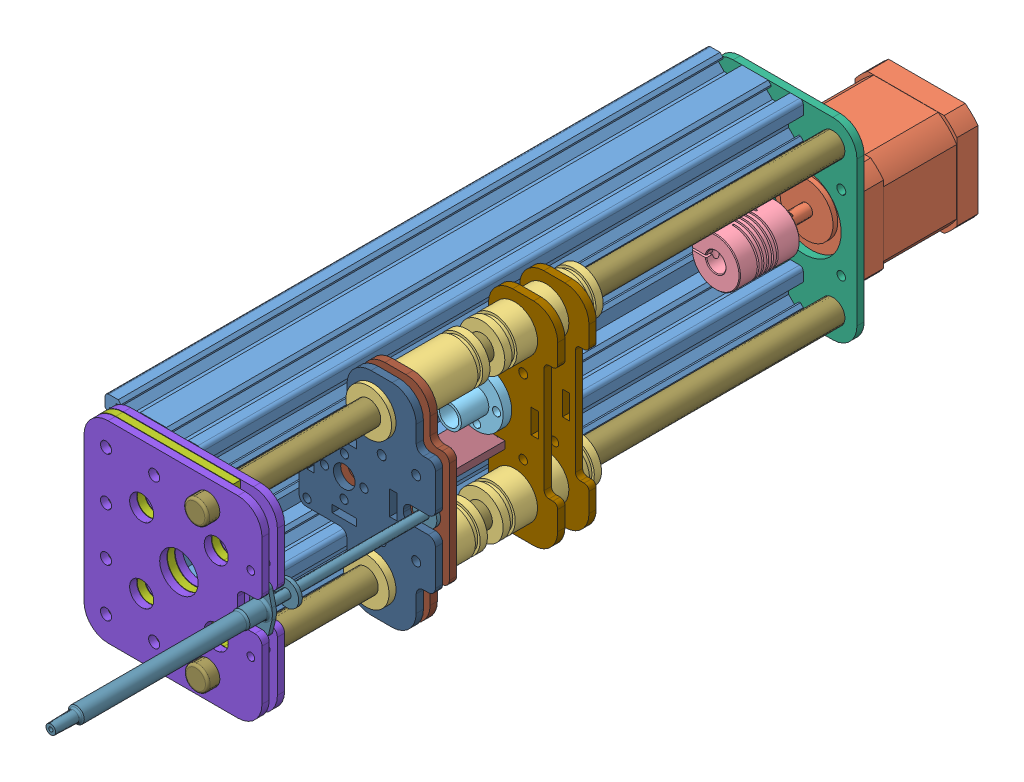
SolidWorks assembly pump_asembly02, configuration Default. Lengths in mm.
Overall size (78.17 88.03 393.93).
21 component instances, 15 part files, 31 mates.
Components (placement in the parent):
- C-Beam 40x80x250 Linear Rail-2: C-Beam 40x80x250 Linear Rail [Default] at (125.6746 -111.8662 -206.616) size (40 80 250)
- Nema 17 Stepper Motor-2: Nema 17 Stepper Motor [Default] at (145.9607 -111.6142 -209.692) size (42.42 42.42 72)
- bushing_10mm_id-1: bushing_10mm_id [Default] at (157.9607 -141.5917 -78.1172) x (0 0 -1) z (0.995692 -0.092726 0) size (40.86 19 19)
- bushing_10mm_id-2: bushing_10mm_id [Default] at (157.9607 -81.5917 -78.7968) x (0 0 -1) z (0.890907 0.454185 0) size (40.86 19 19)
- bushing_10mm_id-3: bushing_10mm_id [Default] at (157.9607 -141.5917 -30.7122) x (0 0 -1) z (0.92037 0.391048 0) size (40.86 19 19)
- bushing_10mm_id-4: bushing_10mm_id [Default] at (157.9607 -81.5917 -31.7606) x (0 0 -1) z (0.909573 -0.415544 0) size (40.86 19 19)
- Flexible Coupling 5mm x 8mm-1: Flexible Coupling 5mm x 8mm [Default] at (145.9021 -111.68 -194.9764) x (-1 0 0) z (0 0 -1) size (21.03 20 25)
- acme_nut_8mm-2: acme_nut_8mm [Default] at (145.9711 -111.5837 -74.1996) x (-1 0 0) z (0 1 0) size (22 15 22)
- laser_cut_end_plates_3mm-1: laser_cut_end_plates_3mm [Default] at (0 0 -209.616) size (61.43 80.03 3)
- laser_cut_front_plate_flat_3mm-1: laser_cut_front_plate_flat_3mm [Default] at (0 0 46.8527) size (58.85 80.03 3)
- laser_cut_front_plate_holder_3mm-1: laser_cut_front_plate_holder_3mm [Default] at (0 0 43.6398) size (73.95 80.03 3)
- laser_cut_front_plate_holder_3mm-2: laser_cut_front_plate_holder_3mm [Default] at (0 0 50.0374) size (73.95 80.03 3)
- laser_cut_slide_blank_3mm-1: laser_cut_slide_blank_3mm [Default] at (0 0 -90.4323) size (48.64 88.03 3)
- laser_cut_slide_front_3mm-1: laser_cut_slide_front_3mm [Default] at (0 0 -18.6437) size (56.64 88.03 3)
- laser_cut_slide_back_3mm-1: laser_cut_slide_back_3mm [Default] at (0 0 -24.4323) size (56.64 88.03 3)
- laser_cut_slide_blank_3mm-2: laser_cut_slide_blank_3mm [Default] at (0 0 -77.4323) size (48.64 88.03 3)
- rail_10mm_270mm-1: rail_10mm_270mm [Default] at (157.9607 -81.5917 58.2557) x (0 0 -1) z (0.966681 0.255983 0) size (270 10 10)
- rail_10mm_270mm-2: rail_10mm_270mm [Default] at (157.9607 -141.5917 58.0229) x (0 0 -1) z (0.989738 0.142896 0) size (270 10 10)
- laser_cut_spacer_50mm_3mm-1: laser_cut_spacer_50mm_3mm [Default] at (145.6286 -127.0917 -24.4323) x (0 0 1) z (-1 0 0) size (52.79 3 16.1)
- syringe_1ml-2: syringe_1ml [Default] at (178.4766 -111.6295 136.2346) x (0 0 -1) z (0 1 0) size (156.81 10.2 19)
- laser_cut_spacer_10mm_3mm-2: laser_cut_spacer_10mm_3mm [Default] at (146.1928 -99.0917 -87.4323) x (0 0 -1) z (1 0 0) size (12.76 3 16.1)
Mates (geometry in assembly coordinates):
- Concentric1: concentric aligned: cylinder of C-Beam 40x80x250 Linear Rail-2 through (115.6746 -81.8662 43.384) axis (0 0 -1) radius 2.3; cylinder of laser_cut_end_plates_3mm-1 through (115.6746 -81.8662 -206.616) axis (0 0 -1) radius 2.3
- Concentric2: concentric aligned: cylinder of C-Beam 40x80x250 Linear Rail-2 through (115.6746 -141.8662 43.384) axis (0 0 -1) radius 2.3; cylinder of laser_cut_end_plates_3mm-1 through (115.6746 -141.8662 -206.616) axis (0 0 -1) radius 2.3
- Coincident1: coincident anti-aligned: plane of C-Beam 40x80x250 Linear Rail-2 through (125.6746 -111.8662 -206.616) normal (0 0 -1); plane of laser_cut_end_plates_3mm-1 through (157.9607 -141.8968 -206.616) normal (0 0 1)
- Concentric3: concentric anti-aligned: cylinder of laser_cut_end_plates_3mm-1 through (157.9607 -81.5917 -206.616) axis (0 0 -1) radius 5; cylinder of rail_10mm_270mm-1 through (157.9607 -81.5917 -211.7443) axis (0 0 1) radius 5
- Concentric4: concentric anti-aligned: cylinder of laser_cut_end_plates_3mm-1 through (157.9607 -141.5917 -206.616) axis (0 0 -1) radius 5; cylinder of rail_10mm_270mm-2 through (157.9607 -141.5917 -211.9771) axis (0 0 1) radius 5
- Concentric5: concentric aligned: cylinder of bushing_10mm_id-4 through (157.9607 -81.5917 6.9932) axis (0 0 1) radius 5; cylinder of rail_10mm_270mm-1 through (157.9607 -81.5917 -211.7443) axis (0 0 1) radius 5
- Concentric6: concentric aligned: cylinder of bushing_10mm_id-3 through (157.9607 -141.5917 8.0416) axis (0 0 1) radius 5; cylinder of rail_10mm_270mm-2 through (157.9607 -141.5917 -211.9771) axis (0 0 1) radius 5
- Concentric7: concentric aligned: cylinder of bushing_10mm_id-2 through (157.9607 -81.5917 -40.043) axis (0 0 1) radius 5; cylinder of rail_10mm_270mm-1 through (157.9607 -81.5917 -211.7443) axis (0 0 1) radius 5
- Concentric8: concentric aligned: cylinder of bushing_10mm_id-1 through (157.9607 -141.5917 -39.3634) axis (0 0 1) radius 5; cylinder of rail_10mm_270mm-2 through (157.9607 -141.5917 -211.9771) axis (0 0 1) radius 5
- Tangent2: tangent aligned: cylinder of rail_10mm_270mm-1 through (157.9607 -81.5917 -211.7443) axis (0 0 1) radius 5; cylinder of laser_cut_front_plate_holder_3mm-1 through (157.9607 -81.5917 46.6398) axis (0 0 -1) radius 5
- Concentric10: concentric anti-aligned: cylinder of laser_cut_front_plate_holder_3mm-1 through (157.9607 -141.5917 46.6398) axis (0 0 -1) radius 5; cylinder of rail_10mm_270mm-2 through (157.9607 -141.5917 -211.9771) axis (0 0 1) radius 5
- Concentric11: concentric anti-aligned: cylinder of laser_cut_front_plate_flat_3mm-1 through (157.9607 -81.5917 49.8527) axis (0 0 -1) radius 5; cylinder of rail_10mm_270mm-1 through (157.9607 -81.5917 -211.7443) axis (0 0 1) radius 5
- Concentric12: concentric anti-aligned: cylinder of laser_cut_front_plate_flat_3mm-1 through (157.9607 -141.5917 49.8527) axis (0 0 -1) radius 5; cylinder of rail_10mm_270mm-2 through (157.9607 -141.5917 -211.9771) axis (0 0 1) radius 5
- Concentric13: concentric anti-aligned: cylinder of laser_cut_front_plate_holder_3mm-2 through (157.9607 -81.5917 53.0374) axis (0 0 -1) radius 5; cylinder of rail_10mm_270mm-1 through (157.9607 -81.5917 -211.7443) axis (0 0 1) radius 5
- Concentric14: concentric anti-aligned: cylinder of laser_cut_front_plate_holder_3mm-2 through (157.9607 -141.5917 53.0374) axis (0 0 -1) radius 5; cylinder of rail_10mm_270mm-2 through (157.9607 -141.5917 -211.9771) axis (0 0 1) radius 5
- Concentric15: concentric anti-aligned: cylinder of laser_cut_slide_blank_3mm-2 through (157.9607 -81.5917 -74.4323) axis (0 0 -1) radius 9.5; cylinder of rail_10mm_270mm-1 through (157.9607 -81.5917 -211.7443) axis (0 0 1) radius 5
- Concentric16: concentric anti-aligned: cylinder of laser_cut_slide_blank_3mm-2 through (157.9607 -141.5917 -74.4323) axis (0 0 -1) radius 9.5; cylinder of rail_10mm_270mm-2 through (157.9607 -141.5917 -211.9771) axis (0 0 1) radius 5
- Concentric17: concentric anti-aligned: cylinder of laser_cut_slide_front_3mm-1 through (157.9607 -81.5917 -15.6437) axis (0 0 -1) radius 9.5; cylinder of rail_10mm_270mm-1 through (157.9607 -81.5917 -211.7443) axis (0 0 1) radius 5
- Concentric18: concentric anti-aligned: cylinder of laser_cut_slide_front_3mm-1 through (157.9607 -141.5917 -15.6437) axis (0 0 -1) radius 9.5; cylinder of rail_10mm_270mm-2 through (157.9607 -141.5917 -211.9771) axis (0 0 1) radius 5
- Concentric19: concentric anti-aligned: cylinder of laser_cut_slide_blank_3mm-1 through (157.9607 -81.5917 -87.4323) axis (0 0 -1) radius 9.5; cylinder of rail_10mm_270mm-1 through (157.9607 -81.5917 -211.7443) axis (0 0 1) radius 5
- Concentric20: concentric anti-aligned: cylinder of laser_cut_slide_blank_3mm-1 through (157.9607 -141.5917 -87.4323) axis (0 0 -1) radius 9.5; cylinder of rail_10mm_270mm-2 through (157.9607 -141.5917 -211.9771) axis (0 0 1) radius 5
- Concentric21: concentric anti-aligned: cylinder of laser_cut_slide_back_3mm-1 through (157.9607 -81.5917 -21.4323) axis (0 0 -1) radius 9.5; cylinder of rail_10mm_270mm-1 through (157.9607 -81.5917 -211.7443) axis (0 0 1) radius 5
- Concentric22: concentric anti-aligned: cylinder of laser_cut_slide_back_3mm-1 through (157.9607 -141.5917 -21.4323) axis (0 0 -1) radius 9.5; cylinder of rail_10mm_270mm-2 through (157.9607 -141.5917 -211.9771) axis (0 0 1) radius 5
- Coincident2: coincident anti-aligned: plane of laser_cut_slide_blank_3mm-2 through (0 0 -74.4323) normal (0 0 1); plane of laser_cut_spacer_50mm_3mm-1 through (153.9607 -124.0917 -74.4323) normal (0 0 -1)
- Coincident3: coincident anti-aligned: plane of laser_cut_slide_blank_3mm-2 through (150.9607 -127.0917 -74.4323) normal (-1 0 0); plane of laser_cut_spacer_50mm_3mm-1 through (150.9607 -124.0917 -74.6776) normal (1 0 0)
- Coincident4: coincident anti-aligned: plane of laser_cut_slide_blank_3mm-2 through (140.9607 -127.0917 -74.4323) normal (0 1 0); plane of laser_cut_spacer_50mm_3mm-1 through (150.9607 -127.0917 -74.4323) normal (0 -1 0)
- Coincident5: coincident anti-aligned: plane of laser_cut_slide_back_3mm-1 through (0 0 -24.4323) normal (0 0 -1); plane of laser_cut_spacer_50mm_3mm-1 through (151.2107 -124.0917 -24.4323) normal (0 0 1)
- Coincident10: coincident anti-aligned: plane of laser_cut_slide_blank_3mm-2 through (140.9607 -99.0917 -74.4323) normal (0 1 0); plane of laser_cut_spacer_10mm_3mm-2 through (150.9607 -99.0917 -87.4323) normal (0 -1 0)
- Coincident11: coincident anti-aligned: plane of laser_cut_slide_blank_3mm-2 through (150.9607 -99.0917 -74.4323) normal (-1 0 0); plane of laser_cut_spacer_10mm_3mm-2 through (150.9607 -96.0917 -77.1823) normal (1 0 0)
- Coincident12: coincident anti-aligned: plane of laser_cut_slide_blank_3mm-2 through (0 0 -77.4323) normal (0 0 -1); plane of laser_cut_spacer_10mm_3mm-2 through (153.9607 -96.0917 -77.4323) normal (0 0 1)
- Coincident13: coincident anti-aligned: plane of laser_cut_slide_blank_3mm-1 through (0 0 -87.4323) normal (0 0 1); plane of laser_cut_spacer_10mm_3mm-2 through (151.2107 -96.0917 -87.4323) normal (0 0 -1)
